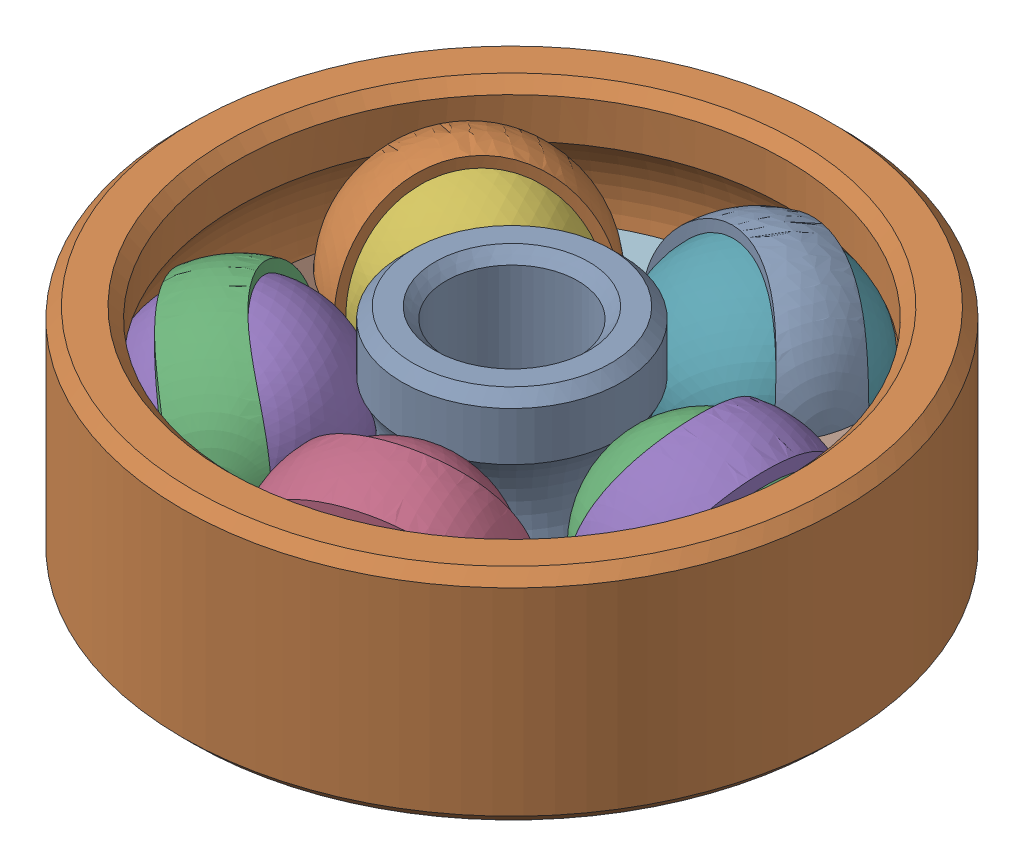
SolidWorks assembly ___108548, configuration Default. Lengths in mm.
Overall size (12.6 5.92 12.55).
8 component instances, 4 part files, 1 mates.
Components (placement in the parent):
- ___108544-1: ___108544 [Default] at origin size (4 4 4)
- ___108547-1: ___108547 [Default] at origin size (12 4 12)
- ___108545-2: ___108545 [Default] at (3.55 0.005 0) x (-0.680051 -0.505217 -0.531306) z (0.399158 0.352731 -0.846317) size (3.6 3.6 3.6)
- ___108545-3: ___108545 [Default] at (1.097 0.005 3.3762) x (0.295155 -0.505217 -0.81095) z (0.928242 0.352731 0.118096) size (3.6 3.6 3.6)
- ___108545-4: ___108545 [Default] at (-2.872 0.005 2.0866) x (0.862467 -0.505217 0.030112) z (0.174527 0.352731 0.919305) size (3.6 3.6 3.6)
- ___108545-5: ___108545 [Default] at (-2.872 0.005 -2.0866) x (0.237879 -0.505217 0.82956) z (-0.820379 0.352731 0.450066) size (3.6 3.6 3.6)
- ___108545-6: ___108545 [Default] at (1.097 0.005 -3.3762) x (-0.71545 -0.505217 0.482584) z (-0.681549 0.352731 -0.641149) size (3.6 3.6 3.6)
- ___108546-1: ___108546 [Default] at origin size (9.22 4 9.2)
Mates (geometry in assembly coordinates):
- Distance3: distance = 3.55 mm: point of ___108545-2; point of assembly
